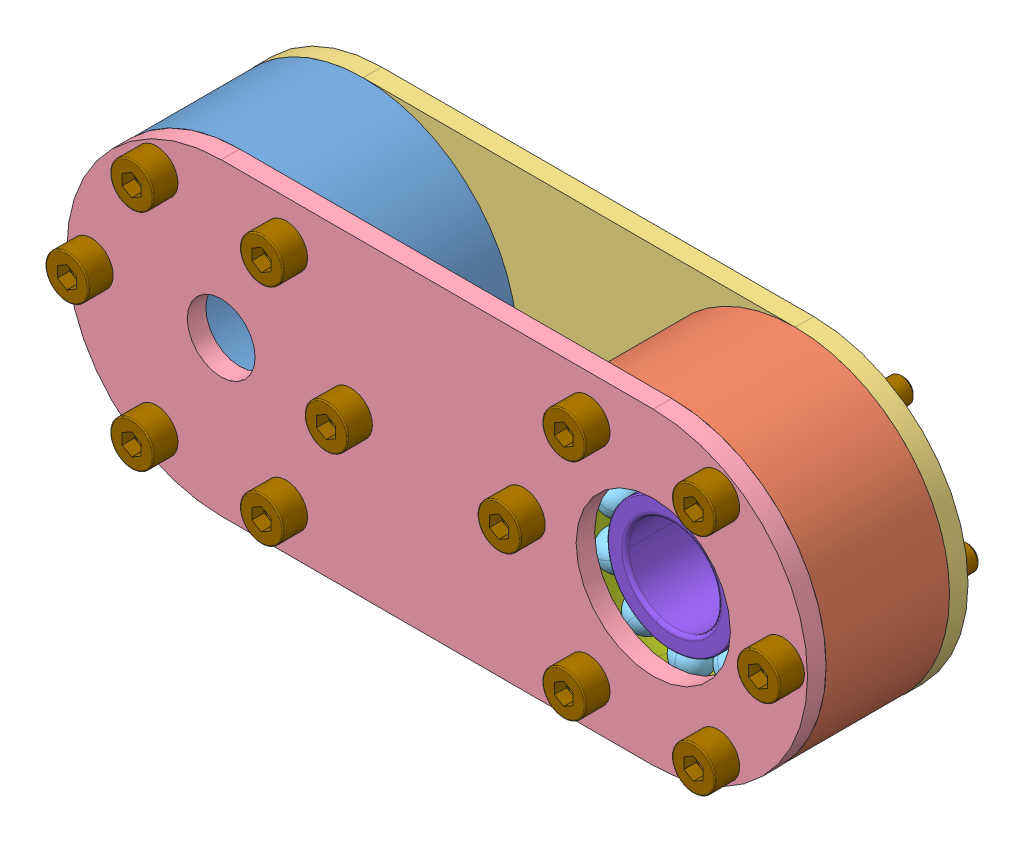
SolidWorks assembly manivela con rodamiento, configuration Predeterminado. Lengths in mm.
Overall size (120 50 34).
40 component instances, 10 part files, 37 mates.
Components (placement in the parent):
- cople flecha-1: cople flecha [Predeterminado] at origin size (50 50 20)
- cople rodamiento-1: cople rodamiento [Predeterminado] at (70 0 0) size (50 50 20)
- placa manivela-1: placa manivela [Predeterminado] at (0 0 -3) size (120 50 3)
- placa manivela 2-2: placa manivela 2 [Predeterminado] at (0 0 20) size (120 50 3)
- 2202_ETN9-1: 2202_ETN9 [Default] at (70 0 20) x (0 0 -1) z (1 0 0) size (14 35 35)
  - 2202_ETN9_3-1: 2202_ETN9_3 [Default] x (1 0 0) z (0 -0.587785 0.809017) size (6 6 6)
  - 2202_ETN9_3-2: 2202_ETN9_3 [Default] x (1 0 0) z (0 -0.951057 0.309017) size (6 6 6)
  - 2202_ETN9_3-3: 2202_ETN9_3 [Default] x (1 0 0) z (0 -0.951057 -0.309017) size (6 6 6)
  - 2202_ETN9_3-4: 2202_ETN9_3 [Default] x (1 0 0) z (0 -0.587785 -0.809017) size (6 6 6)
  - 2202_ETN9_3-5: 2202_ETN9_3 [Default] x (1 0 0) z (0 0 -1) size (6 6 6)
  - 2202_ETN9_3-6: 2202_ETN9_3 [Default] x (1 0 0) z (0 0.587785 -0.809017) size (6 6 6)
  - 2202_ETN9_3-7: 2202_ETN9_3 [Default] x (1 0 0) z (0 0.951057 -0.309017) size (6 6 6)
  - 2202_ETN9_3-8: 2202_ETN9_3 [Default] x (1 0 0) z (0 0.951057 0.309017) size (6 6 6)
  - 2202_ETN9_3-9: 2202_ETN9_3 [Default] x (1 0 0) z (0 0.587785 0.809017) size (6 6 6)
  - 2202_ETN9_3-10: 2202_ETN9_3 [Default] at origin size (6 6 6)
  - 2202_ETN9_14-1: 2202_ETN9_14 [Default] x (1 0 0) z (0 -0.587785 0.809017) size (6 6 6)
  - 2202_ETN9_14-2: 2202_ETN9_14 [Default] x (1 0 0) z (0 -0.951057 0.309017) size (6 6 6)
  - 2202_ETN9_14-3: 2202_ETN9_14 [Default] x (1 0 0) z (0 -0.951057 -0.309017) size (6 6 6)
  - 2202_ETN9_14-4: 2202_ETN9_14 [Default] x (1 0 0) z (0 -0.587785 -0.809017) size (6 6 6)
  - 2202_ETN9_14-5: 2202_ETN9_14 [Default] x (1 0 0) z (0 0 -1) size (6 6 6)
  - 2202_ETN9_14-6: 2202_ETN9_14 [Default] x (1 0 0) z (0 0.587785 -0.809017) size (6 6 6)
  - 2202_ETN9_14-7: 2202_ETN9_14 [Default] x (1 0 0) z (0 0.951057 -0.309017) size (6 6 6)
  - 2202_ETN9_14-8: 2202_ETN9_14 [Default] x (1 0 0) z (0 0.951057 0.309017) size (6 6 6)
  - 2202_ETN9_14-9: 2202_ETN9_14 [Default] x (1 0 0) z (0 0.587785 0.809017) size (6 6 6)
  - 2202_ETN9_14-10: 2202_ETN9_14 [Default] at origin size (6 6 6)
  - 2202_ETN9_29-1: 2202_ETN9_29 [Default] at origin size (14 35 35)
  - 2202_ETN9_31-1: 2202_ETN9_31 [Default] at origin size (14 20.86 20.86)
- socket head cap screw_iso-16: socket head cap screw_iso [ISO 4762 M4 x 30 - 20N] at (-10.5 18.1865 27) x (0 0 -1) z (1 0 0) size (34 7 7)
- socket head cap screw_iso-17: socket head cap screw_iso [ISO 4762 M4 x 30 - 20N] at (10.5 18.1865 27) x (0 0 -1) z (1 0 0) size (34 7 7)
- socket head cap screw_iso-18: socket head cap screw_iso [ISO 4762 M4 x 30 - 20N] at (21 0 27) x (0 0 -1) z (1 0 0) size (34 7 7)
- socket head cap screw_iso-19: socket head cap screw_iso [ISO 4762 M4 x 30 - 20N] at (10.5 -18.1865 27) x (0 0 -1) z (1 0 0) size (34 7 7)
- socket head cap screw_iso-20: socket head cap screw_iso [ISO 4762 M4 x 30 - 20N] at (-10.5 -18.1865 27) x (0 0 -1) z (1 0 0) size (34 7 7)
- socket head cap screw_iso-21: socket head cap screw_iso [ISO 4762 M4 x 30 - 20N] at (-21 0 27) x (0 0 -1) z (1 0 0) size (34 7 7)
- socket head cap screw_iso-22: socket head cap screw_iso [ISO 4762 M4 x 30 - 20N] at (59.5 18.1865 27) x (0 0 -1) z (1 0 0) size (34 7 7)
- socket head cap screw_iso-23: socket head cap screw_iso [ISO 4762 M4 x 30 - 20N] at (49 0 27) x (0 0 -1) z (1 0 0) size (34 7 7)
- socket head cap screw_iso-24: socket head cap screw_iso [ISO 4762 M4 x 30 - 20N] at (59.5 -18.1865 27) x (0 0 -1) z (1 0 0) size (34 7 7)
- socket head cap screw_iso-25: socket head cap screw_iso [ISO 4762 M4 x 30 - 20N] at (80.5 -18.1865 27) x (0 0 -1) z (1 0 0) size (34 7 7)
- socket head cap screw_iso-26: socket head cap screw_iso [ISO 4762 M4 x 30 - 20N] at (91 0 27) x (0 0 -1) z (1 0 0) size (34 7 7)
- socket head cap screw_iso-27: socket head cap screw_iso [ISO 4762 M4 x 30 - 20N] at (80.5 18.1865 27) x (0 0 -1) z (1 0 0) size (34 7 7)
- anillo manivela-1: anillo manivela [Predeterminado] at (70 0 0) size (35 35 6)
Mates (geometry in assembly coordinates):
- Coincidente1: coincident anti-aligned: plane of cople flecha-1 through (0 0 0) normal (0 0 -1); plane of placa manivela-1 through (0 0 0) normal (0 0 1)
- Concéntrica1: concentric aligned: cylinder of cople flecha-1 through (0 0 0) axis (0 0 1) radius 13; cylinder of placa manivela-1 through (0 0 -3) axis (0 0 1) radius 13
- Concéntrica2: concentric aligned: cylinder of cople flecha-1 through (-10.5 18.1865 20) axis (0 0 1) radius 2.15; cylinder of placa manivela-1 through (-10.5 18.1865 0) axis (0 0 1) radius 2.25
- Concéntrica3: concentric anti-aligned: circle of cople rodamiento-1; cylinder of 2202_ETN9-1/2202_ETN9_29-1 through (70 0 -30) axis (0 0 -1) radius 17.5
- Coincidente3: coincident aligned: plane of cople rodamiento-1 through (70 0 20) normal (0 0 1); plane of 2202_ETN9-1/2202_ETN9_29-1 through (70 16.9 20) normal (0 0 1)
- Coincidente4: coincident anti-aligned: plane of cople rodamiento-1 through (70 0 0) normal (0 0 -1); plane of placa manivela-1 through (0 0 0) normal (0 0 1)
- Concéntrica4: concentric aligned: cylinder of cople rodamiento-1 through (70 0 20) axis (0 0 -1) radius 25; cylinder of placa manivela-1 through (70 0 0) axis (0 0 -1) radius 25
- Concéntrica5: concentric aligned: cylinder of cople rodamiento-1 through (91 0 20) axis (0 0 1) radius 2.15; cylinder of placa manivela-1 through (91 0 0) axis (0 0 1) radius 2.25
- Coincidente5: coincident anti-aligned: plane of cople flecha-1 through (0 0 20) normal (0 0 1); plane of placa manivela 2-2 through (0 0 20) normal (0 0 -1)
- Concéntrica6: concentric aligned: cylinder of cople flecha-1 through (0 0 0) axis (0 0 1) radius 13; cylinder of placa manivela 2-2 through (0 0 23) axis (0 0 1) radius 5.5
- Concéntrica7: concentric aligned: cylinder of cople rodamiento-1 through (59.5 18.1865 20) axis (0 0 1) radius 2.15; cylinder of placa manivela 2-2 through (59.5 18.1865 23) axis (0 0 1) radius 2.25
- Concéntrica8: concentric aligned: cylinder of placa manivela 2-2 through (-10.5 18.1865 23) axis (0 0 1) radius 2.25; cylinder of socket head cap screw_iso-16 through (-10.5 18.1865 58.75) axis (0 0 1) radius 3.5
- Coincidente6: coincident anti-aligned: plane of placa manivela 2-2 through (0 0 23) normal (0 0 1); plane of socket head cap screw_iso-16 through (-10.5 21.6865 23) normal (0 0 -1)
- Concéntrica9: concentric aligned: cylinder of placa manivela 2-2 through (10.5 18.1865 23) axis (0 0 1) radius 2.25; cylinder of socket head cap screw_iso-17 through (10.5 18.1865 58.75) axis (0 0 1) radius 3.5
- Coincidente7: coincident anti-aligned: plane of placa manivela 2-2 through (0 0 23) normal (0 0 1); plane of socket head cap screw_iso-17 through (10.5 21.6865 23) normal (0 0 -1)
- Concéntrica10: concentric aligned: cylinder of placa manivela 2-2 through (21 0 23) axis (0 0 1) radius 2.25; cylinder of socket head cap screw_iso-18 through (21 0 58.75) axis (0 0 1) radius 3.5
- Coincidente8: coincident anti-aligned: plane of placa manivela 2-2 through (0 0 23) normal (0 0 1); plane of socket head cap screw_iso-18 through (21 3.5 23) normal (0 0 -1)
- Concéntrica11: concentric aligned: cylinder of placa manivela 2-2 through (10.5 -18.1865 23) axis (0 0 1) radius 2.25; cylinder of socket head cap screw_iso-19 through (10.5 -18.1865 58.75) axis (0 0 1) radius 3.5
- Coincidente9: coincident anti-aligned: plane of placa manivela 2-2 through (0 0 23) normal (0 0 1); plane of socket head cap screw_iso-19 through (10.5 -14.6865 23) normal (0 0 -1)
- Concéntrica12: concentric aligned: cylinder of placa manivela 2-2 through (-10.5 -18.1865 23) axis (0 0 1) radius 2.25; cylinder of socket head cap screw_iso-20 through (-10.5 -18.1865 58.75) axis (0 0 1) radius 3.5
- Coincidente10: coincident anti-aligned: plane of placa manivela 2-2 through (0 0 23) normal (0 0 1); plane of socket head cap screw_iso-20 through (-10.5 -14.6865 23) normal (0 0 -1)
- Concéntrica13: concentric aligned: cylinder of placa manivela 2-2 through (-21 0 23) axis (0 0 1) radius 2.25; cylinder of socket head cap screw_iso-21 through (-21 0 58.75) axis (0 0 1) radius 3.5
- Coincidente11: coincident anti-aligned: plane of placa manivela 2-2 through (0 0 23) normal (0 0 1); plane of socket head cap screw_iso-21 through (-21 3.5 23) normal (0 0 -1)
- Concéntrica14: concentric aligned: cylinder of placa manivela 2-2 through (59.5 18.1865 23) axis (0 0 1) radius 2.25; cylinder of socket head cap screw_iso-22 through (59.5 18.1865 58.75) axis (0 0 1) radius 3.5
- Coincidente12: coincident anti-aligned: plane of placa manivela 2-2 through (0 0 23) normal (0 0 1); plane of socket head cap screw_iso-22 through (59.5 21.6865 23) normal (0 0 -1)
- Concéntrica15: concentric aligned: cylinder of placa manivela 2-2 through (49 0 23) axis (0 0 1) radius 2.25; cylinder of socket head cap screw_iso-23 through (49 0 58.75) axis (0 0 1) radius 3.5
- Coincidente13: coincident anti-aligned: plane of placa manivela 2-2 through (0 0 23) normal (0 0 1); plane of socket head cap screw_iso-23 through (49 3.5 23) normal (0 0 -1)
- Concéntrica16: concentric aligned: cylinder of placa manivela 2-2 through (59.5 -18.1865 23) axis (0 0 1) radius 2.25; cylinder of socket head cap screw_iso-24 through (59.5 -18.1865 58.75) axis (0 0 1) radius 3.5
- Coincidente14: coincident anti-aligned: plane of placa manivela 2-2 through (0 0 23) normal (0 0 1); plane of socket head cap screw_iso-24 through (59.5 -14.6865 23) normal (0 0 -1)
- Concéntrica17: concentric aligned: cylinder of placa manivela 2-2 through (80.5 -18.1865 23) axis (0 0 1) radius 2.25; cylinder of socket head cap screw_iso-25 through (80.5 -18.1865 58.75) axis (0 0 1) radius 3.5
- Coincidente15: coincident anti-aligned: plane of placa manivela 2-2 through (0 0 23) normal (0 0 1); plane of socket head cap screw_iso-25 through (80.5 -14.6865 23) normal (0 0 -1)
- Concéntrica18: concentric aligned: cylinder of placa manivela 2-2 through (91 0 23) axis (0 0 1) radius 2.25; cylinder of socket head cap screw_iso-26 through (91 0 58.75) axis (0 0 1) radius 3.5
- Coincidente16: coincident anti-aligned: plane of placa manivela 2-2 through (0 0 23) normal (0 0 1); plane of socket head cap screw_iso-26 through (91 3.5 23) normal (0 0 -1)
- Concéntrica19: concentric aligned: cylinder of placa manivela 2-2 through (80.5 18.1865 23) axis (0 0 1) radius 2.25; cylinder of socket head cap screw_iso-27 through (80.5 18.1865 58.75) axis (0 0 1) radius 3.5
- Coincidente17: coincident anti-aligned: plane of placa manivela 2-2 through (0 0 23) normal (0 0 1); plane of socket head cap screw_iso-27 through (80.5 21.6865 23) normal (0 0 -1)
- Concéntrica20: concentric aligned: cylinder of cople rodamiento-1 through (70 0 20) axis (0 0 -1) radius 17.5; cylinder of anillo manivela-1 through (70 0 6) axis (0 0 -1) radius 17.5
- Coincidente18: coincident anti-aligned: plane of placa manivela-1 through (0 0 0) normal (0 0 1); plane of anillo manivela-1 through (70 0 0) normal (0 0 -1)
